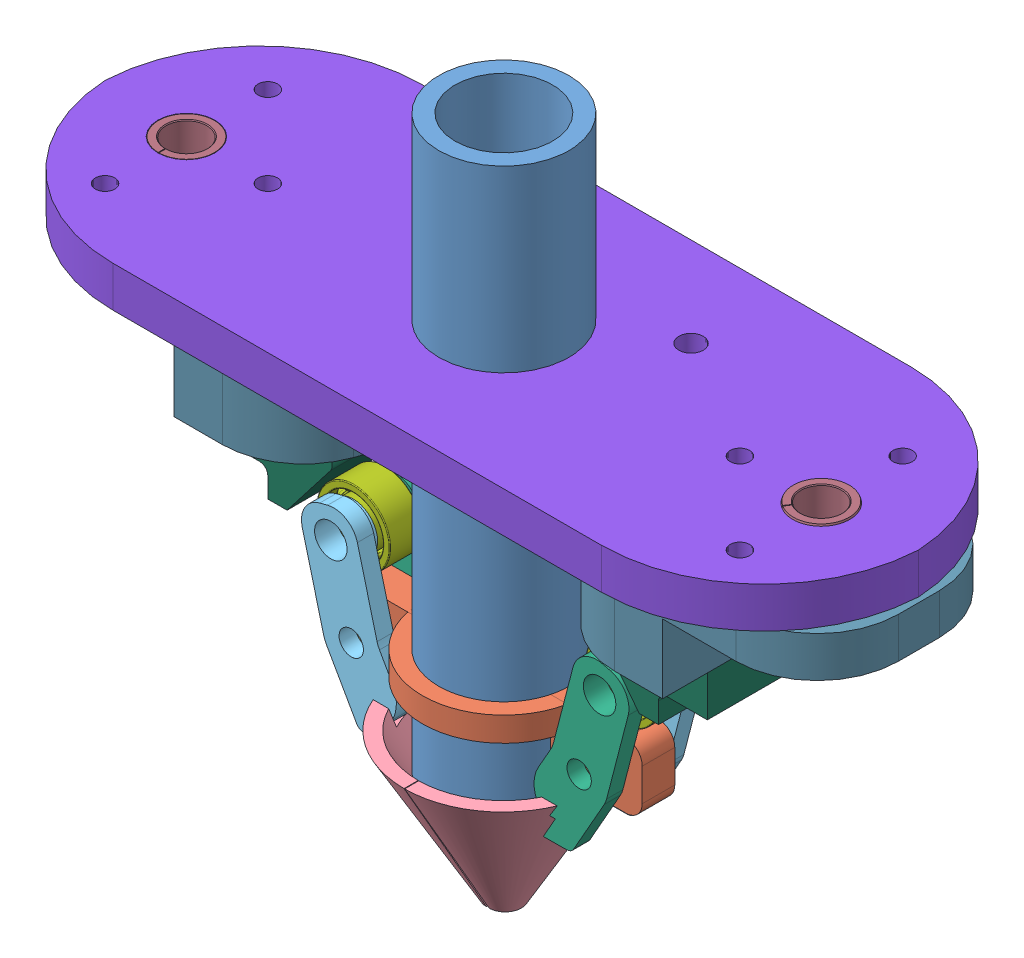
SolidWorks assembly 栽种机构, configuration 默认. Lengths in mm.
Overall size (99.95 83.61 62).
25 component instances, 16 part files, 52 mates.
Components (placement in the parent):
- pipe-1: pipe [默认] at (0 49.3219 44) size (16 70 16)
- pipe_gate_holder-1: pipe_gate_holder [默认] at (0 39.3219 44) size (38 8 20)
- 管门机构-1: 管门机构 [默认] at (-0.072 -20.7891 44) x (0.999968 -0.00795 0) z (0 0 1) size (29.51 35.7 24.46)
  - 卷制轴套3×5×5-1: 卷制轴套3×5×5 [3×5×3] at (-14 9 2.5) x (0 0 -1) z (-0.194187 0.980965 0) size (5 5 5)
  - pipe_gate-1: pipe_gate [默认] at origin size (12.23 17.75 24.46)
  - pipe_gate_lever-1: pipe_gate_lever [默认] at (0 0 40.0025) size (11.77 22.05 2.75)
  - 镜向pipe_gate_lever-4: 镜向pipe_gate_lever [默认] at (0 0 -40.0025) size (11.77 22.05 2.75)
- 深沟球轴承4x9x4-1: 深沟球轴承4x9x4 [618╱4] at (-16.5109 -1.9985 44) x (0 0 1) z (0.999871 0.016085 0) size (4 9 9)
- 苗管固定板-1: 苗管固定板 [默认] at (0 22.3219 44) size (99.95 5 38)
- 升降曲柄-1: 升降曲柄 [默认] at (0 0 18) x (0 0 1) z (-0.988127 -0.153639 0) size (5.5 27.5 16)
- 升降引导槽-1: 升降引导槽 [默认] at (0 14.8219 29) x (0 0 1) z (-1 0 0) size (17 15 50)
- 升降曲柄主轴-1: 升降曲柄主轴 [默认] x (0 0 1) z (-0.988127 -0.153639 0) size (23 4 4)
- 升降曲柄从轴-1: 升降曲柄从轴 [默认] at (-2.3046 14.8219 18) x (0 0 1) z (-0.988127 -0.153639 0) size (16.5 3 3)
- 轴套5×7×5-1: 轴套5×7×5 [5×6×5] at (-39 27.3219 44) x (0 -1 0) z (-1 0 0) size (5 7 7)
- 轴套5×7×5-2: 轴套5×7×5 [5×6×5] at (39 22.5219 44) x (0 1 0) z (0.837169 0 0.546944) size (5 7 7)
- 深沟球轴承4x9x4-2: 深沟球轴承4x9x4 [618╱4] at (16.5109 -1.9985 44) x (0 0 -1) z (-0.714472 0.699664 0) size (4 9 9)
- 管门机构-3: 管门机构 [默认] at (0.072 -20.7891 44) x (-0.999968 -0.00795 0) z (0 0 -1) size (29.51 35.7 24.46)
  - 卷制轴套3×5×5-1: 卷制轴套3×5×5 [3×5×3] at (-14 9 2.5) x (0 0 -1) z (-0.194187 0.980965 0) size (5 5 5)
  - pipe_gate-1: pipe_gate [默认] at origin size (12.23 17.75 24.46)
  - pipe_gate_lever-1: pipe_gate_lever [默认] at (0 0 40.0025) size (11.77 22.05 2.75)
  - 镜向pipe_gate_lever-4: 镜向pipe_gate_lever [默认] at (0 0 -40.0025) size (11.77 22.05 2.75)
- 开门凸轮-1: 开门凸轮 [默认] at (17 12.2425 34.5) x (-1 0 0) z (0 0 -1) size (98 13.5 25)
- 开门引导块-1: 开门引导块 [默认] at (0 -11.7575 44) size (13.92 8.5 10)
- 开门引导块-2: 开门引导块 [默认] at (0 -11.7575 44) x (-1 0 0) z (0 0 -1) size (13.92 8.5 10)
- 3x5x10轴承^栽种机构-1: 3x5x10轴承^栽种机构 [默认] at (-2.3046 14.8219 24.5) x (0.927413 -0.374038 0) z (0 0 1) size (5 5 10) (virtual)
Mates (geometry in assembly coordinates):
- 距离7: distance = 43 mm: plane of pipe-1 through (0 -20.6781 44) normal (0 -1 0); plane of 苗管固定板-1 through (0 22.3219 44) normal (0 -1 0)
- 重合7: coincident anti-aligned: plane of 升降引导槽-1 through (25 21.1065 24) normal (0 1 0); plane of 苗管固定板-1 through (0 21.1065 44) normal (0 -1 0)
- 重合8: coincident aligned: plane of pipe-1 through (0 -5.6781 44) normal (0 -1 0); plane of pipe-1 through (0 -5.6781 44) normal (0 -1 0)
- 同心12: concentric aligned: cylinder of pipe-1 through (0 -17.7156 -8.1644) axis (0 1 0) radius 8; cylinder of pipe_gate_holder-1 through (0 -7.7156 -8.1644) axis (0 1 0) radius 10
- 同心13: concentric aligned: cylinder of 升降曲柄-1 through (0 0 23) axis (0 0 -1) radius 2.5; cylinder of 升降曲柄主轴-1 through (0 0 23) axis (0 0 -1) radius 2.5
- 重合9: coincident aligned: plane of 升降曲柄-1 through (0 0 23) normal (0 0 1); plane of 升降曲柄主轴-1 through (0 0 23) normal (0 0 1)
- 重合11: coincident: line of 升降曲柄主轴-1 through (0 0 23) axis (0 0 -1); point of assembly
- 重合13: coincident aligned: plane of 升降曲柄-1; plane of 升降曲柄主轴-1
- 同心14: concentric: cylinder of 升降曲柄-1 through (-6.3137 13.6065 23) axis (0 0 -1) radius 1.5; cylinder of 升降曲柄从轴-1 through (-6.3137 13.6065 34.5) axis (0 0 -1) radius 1.5
- 重合14: coincident aligned: plane of 升降曲柄-1 through (0 0 18) normal (0 0 -1); plane of 升降曲柄从轴-1 through (-6.3137 13.6065 18) normal (0 0 -1)
- 重合15: coincident aligned: plane of 升降曲柄-1; plane of 升降曲柄从轴-1
- 槽口1: slot: cylinder of 升降曲柄从轴-1 through (-6.3137 13.6065 34.5) axis (0 0 -1) radius 1.5; plane of 升降引导槽-1 through (16 11.1065 24) normal (0 1 0); cylinder of 升降引导槽-1 through (16 12.1027 24) axis (0 0 1) radius 2.5
- 同心15: concentric: cylinder of pipe-1 through (0 -17.7156 -8.1644) axis (0 1 0) radius 8; cylinder of 苗管固定板-1 through (0 30.2844 -8.1644) axis (0 -1 0) radius 8
- 宽度6: width anti-aligned: plane of 苗管固定板-1 through (-50 26.1065 24) normal (-1 0 0); plane of 苗管固定板-1 through (50 26.1065 24) normal (1 0 0); plane of 升降引导槽-1 through (25 21.1065 24) normal (1 0 0); plane of 升降引导槽-1 through (-25 21.1065 24) normal (-1 0 0)
- 平行9: parallel anti-aligned: plane of pipe_gate_holder-1 through (18 -4.7156 -10.1644) normal (0 0 -1); plane of 苗管固定板-1 through (-50 30.2844 9.8356) normal (0 0 1)
- 重合20: coincident: plane of 升降曲柄主轴-1; plane of assembly through (0 0 0) normal (0 0 1)
- 重合21: coincident: plane of pipe-1 through (0 49.3219 44) normal (1 0 0); plane of assembly through (0 0 0) normal (1 0 0)
- 同心17: concentric: cylinder of pipe_gate_holder-1 through (-14 -11.6781 46) axis (0 0 -1) radius 2.5; cylinder of 管门机构-1/卷制轴套3×5×5-1 through (-14 -11.6781 46.5) axis (0 0 1) radius 2.5
- 宽度8: width: plane of pipe_gate_holder-1 through (-7.746 -7.6781 42) normal (0 0 -1); plane of pipe_gate_holder-1 through (-19 -7.6781 46) normal (0 0 1); plane of 管门机构-1/卷制轴套3×5×5-1 through (-15.572 -11.9763 46.5) normal (0 0 1); plane of 管门机构-1/卷制轴套3×5×5-1 through (-16.2416 -12.1033 41.5) normal (0 0 -1)
- 重合31: coincident: plane of pipe-1 through (0 49.3219 44) normal (0 0 1); plane of 管门机构-1/pipe_gate-1 through (-0.072 -20.7891 44) normal (0 0 1)
- 同心30: concentric anti-aligned: cylinder of 苗管固定板-1 through (-39 26.5511 44) axis (0 -1 0) radius 3.5; cylinder of 轴套5×7×5-1 through (-39 26.5511 44) axis (0 1 0) radius 3.5
- 重合41: coincident aligned: plane of 苗管固定板-1 through (0 26.5511 44) normal (0 1 0); plane of 轴套5×7×5-1 through (-39 26.5511 46.6) normal (0 1 0)
- 同心31: concentric aligned: cylinder of 苗管固定板-1 through (39 26.5511 44) axis (0 -1 0) radius 3.5; cylinder of 轴套5×7×5-2 through (39 21.7511 44) axis (0 -1 0) radius 3.5
- 重合42: coincident anti-aligned: plane of 苗管固定板-1 through (0 26.5511 44) normal (0 1 0); circle of 轴套5×7×5-2
- 重合43: coincident aligned: plane of 苗管固定板-1 through (-50 26.1065 24) normal (0 0 -1); plane of 升降引导槽-1 through (0 13.6065 24) normal (0 0 -1)
- 同心4: concentric: cylinder of 深沟球轴承4x9x4-1 through (-16.5109 -1.9985 40.5) axis (0 0 -1) radius 2; cylinder of 管门机构-1/pipe_gate_lever-1 through (-16.5109 -1.9985 74.9573) axis (0 0 -1) radius 2
- 同心33: concentric: cylinder of 深沟球轴承4x9x4-2 through (16.5109 -1.9985 47.5) axis (0 0 1) radius 2; cylinder of 管门机构-3/pipe_gate_lever-1 through (16.5109 -1.9985 13.0427) axis (0 0 1) radius 2
- 距离3: distance = 5.5 mm: plane of 升降引导槽-1 through (0 -6.0892 29) normal (0 0 1); plane of 升降曲柄从轴-1 through (-13.7084 -6.0892 34.5) normal (0 0 1)
- 宽度10: width: plane of 管门机构-3/镜向pipe_gate_lever-4 through (0.072 -20.7891 48.75) normal (0 0 1); plane of 管门机构-3/pipe_gate_lever-1 through (0.072 -20.7891 39.25) normal (0 0 -1); plane of 深沟球轴承4x9x4-2 through (15.0416 -3.4988 46) normal (0 0 1); plane of 深沟球轴承4x9x4-2 through (14.5985 -3.9513 42) normal (0 0 -1)
- 宽度11: width anti-aligned: plane of 管门机构-1/镜向pipe_gate_lever-4 through (-0.072 -20.7891 39.25) normal (0 0 -1); plane of 管门机构-1/pipe_gate_lever-1 through (-0.072 -20.7891 48.75) normal (0 0 1); plane of 深沟球轴承4x9x4-1 through (-16.4669 -4.7314 46) normal (0 0 1); plane of 深沟球轴承4x9x4-1 through (-16.4771 -4.0982 42) normal (0 0 -1)
- 重合44: coincident aligned: plane of 升降引导槽-1 through (16 -8.0446 24) normal (0 1 0); plane of 开门凸轮-1 through (-2 -8.0446 29.5) normal (0 1 0)
- 重合45: coincident aligned: plane of 升降引导槽-1 through (16 -8.271 24) normal (0 1 0); plane of 开门凸轮-1 through (17 -8.271 29.5) normal (0 1 0)
- 重合52: coincident anti-aligned: plane of 开门凸轮-1 through (17 10.2844 -22.6644) normal (0 -1 0); plane of 开门引导块-1 through (15.0441 10.2844 -13.1644) normal (0 1 0)
- 重合50: coincident aligned: plane of 开门凸轮-1 through (30 -54.7156 2.3356) normal (1 0 0); plane of 开门引导块-1 through (30 10.2844 -13.1644) normal (1 0 0)
- 重合56: coincident aligned: plane of 开门凸轮-1 through (17 15.2844 -8.1644) normal (0 0 1); plane of 开门引导块-1 through (0 -8.7156 -8.1644) normal (0 0 1)
- 同心34: concentric: cylinder of 升降曲柄从轴-1 through (-2.3046 14.8219 34.5) axis (0 0 -1) radius 1.5; cylinder of 3x5x10轴承^栽种机构-1 through (-2.3046 14.8219 34.5) axis (0 0 -1) radius 1.5
- 重合51: coincident aligned: plane of 升降曲柄从轴-1 through (-2.3046 14.8219 34.5) normal (0 0 1); plane of 3x5x10轴承^栽种机构-1 through (-2.3046 14.8219 34.5) normal (0 0 1)
- 锁定2: lock: unknown of 开门凸轮-1; unknown of 开门引导块-1
- 相切1: tangent: cylinder of 深沟球轴承4x9x4-2 through (16.5109 -1.9985 47.5) axis (0 0 1) radius 4.5; plane of 开门引导块-1 through (21.6293 -1.2575 39) normal (-0.790516 -0.612441 0)
- 凸轮配合相切1: cam tangent: face of 开门凸轮-1; cylinder of 3x5x10轴承^栽种机构-1 through (-2.3046 14.8219 34.5) axis (0 0 -1) radius 2.5
- 锁定3: lock: unknown of 苗管固定板-1; unknown of 升降引导槽-1
- 锁定4: lock: unknown of 升降曲柄-1; unknown of 升降曲柄从轴-1
- 距离6: distance = 1 mm: plane of 升降曲柄-1 through (0 0 23) normal (0 0 1); plane of 升降引导槽-1 through (0 14.8219 24) normal (0 0 -1)
- 槽口3: slot: cylinder of 3x5x10轴承^栽种机构-1 through (-2.3046 14.8219 34.5) axis (0 0 -1) radius 2.5; plane of 升降引导槽-1 through (16 12.3219 24) normal (0 1 0); cylinder of 升降引导槽-1 through (16 14.8219 24) axis (0 0 1) radius 2.5
- 锁定5: lock: unknown of 升降曲柄-1; unknown of 升降曲柄主轴-1
- 同心36: concentric: cylinder of 轴套5×7×5-1 through (-39 27.3219 44) axis (0 1 0) radius 2.5; cylinder of 开门凸轮-1 through (-39 20.7425 44) axis (0 -1 0) radius 3.5
- 重合57: coincident anti-aligned: plane of 管门机构-1/pipe_gate-1 through (0 -17.7156 -8.1644) normal (1 0 0); plane of 管门机构-3/pipe_gate-1 through (0 -17.7156 -8.1644) normal (-1 0 0)
- 锁定6: lock: unknown of pipe-1; unknown of pipe_gate_holder-1
- 锁定7: lock: unknown of pipe-1; unknown of 苗管固定板-1
- 同心37: concentric: cylinder of 轴套5×7×5-2 through (39 22.5219 44) axis (0 -1 0) radius 2.5; cylinder of 开门凸轮-1 through (39 20.7425 44) axis (0 -1 0) radius 3.5
- 锁定8: lock: unknown of 苗管固定板-1; unknown of 轴套5×7×5-2
- 锁定9: lock: unknown of 苗管固定板-1; unknown of 轴套5×7×5-1
